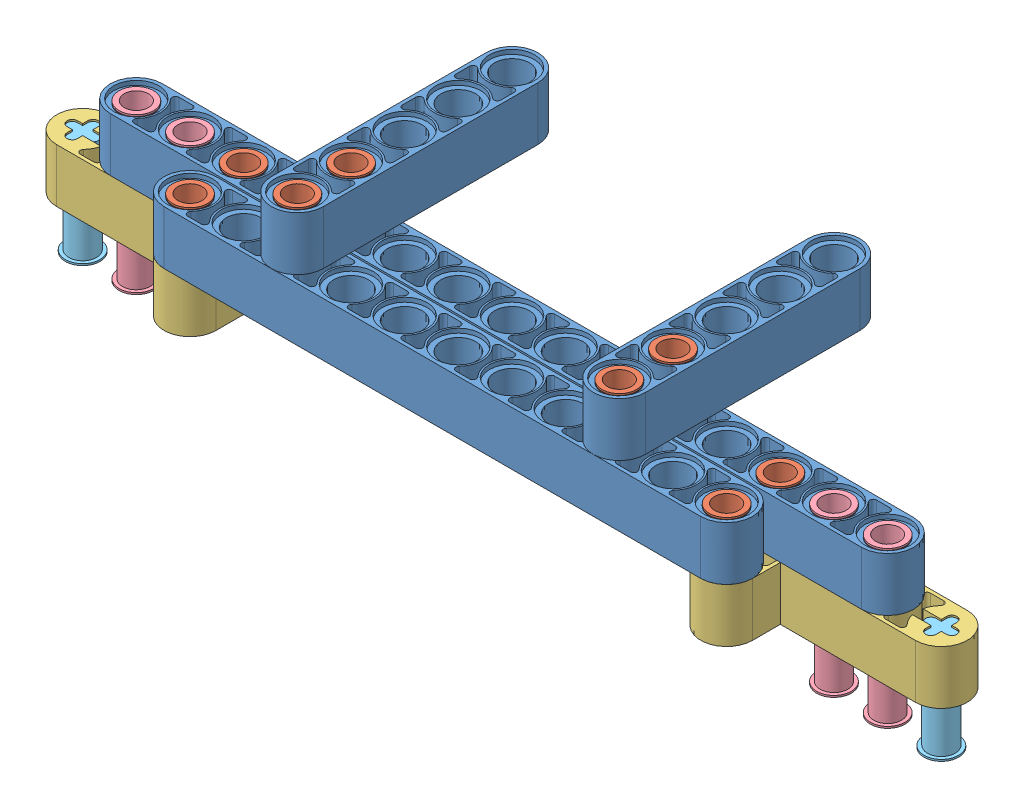
SolidWorks assembly horizontal_connector, configuration Default. Lengths in mm.
Overall size (133.6 31.24 39.12).
20 component instances, 5 part files, 60 mates.
Components (placement in the parent):
- All_Straight-1: All_Straight [Eleven] at (31.496 0 0) x (1 0 0) z (0 1 0) size (86.36 7.62 7.87)
- BlackConnectorSmall-1: BlackConnectorSmall [Default] at (39.37 7.62 0) x (0 -1 0) z (0 0 1) size (15.24 5.59 5.59)
- BlackConnectorSmall-2: BlackConnectorSmall [Default] at (-39.37 7.62 0) x (0 -1 0) z (0 0 1) size (15.24 5.59 5.59)
- BlackConnectorSmall-4: BlackConnectorSmall [Default] at (-23.622 0.254 0) x (0 1 0) z (0 0 -1) size (15.24 5.59 5.59)
- BlackConnectorSmall-5: BlackConnectorSmall [Default] at (23.622 0.254 0) x (0 1 0) z (0 0 -1) size (15.24 5.59 5.59)
- L_Two_Four_90degrees-1: L_Two_Four_90degrees [Default] at (47.4776 -6.6697 -16.0899) x (1 0 0) z (0 -1 0) size (31.24 15.49 7.87)
- L_Two_Four_90degrees-3: L_Two_Four_90degrees [Default] at (-47.4776 -1.2043 -16.0899) x (-1 0 0) z (0 1 0) size (31.24 15.49 7.87)
- BlackConnectorSmall-6: BlackConnectorSmall [Default] at (-39.37 -7.62 -7.874) x (0 1 0) z (0 0 -1) size (15.24 5.59 5.59)
- BlackConnectorSmall-7: BlackConnectorSmall [Default] at (39.37 -7.62 -7.874) x (0 1 0) z (0 0 -1) size (15.24 5.59 5.59)
- BlueConnectorLong-1: BlueConnectorLong [Default] at (47.244 7.62 -7.874) x (0 -1 0) z (-1 0 0) size (22.86 5.59 5.59)
- BlueConnectorLong-2: BlueConnectorLong [Default] at (55.118 7.62 -7.874) x (0 -1 0) z (-1 0 0) size (22.86 5.59 5.59)
- BlueConnectorLong-3: BlueConnectorLong [Default] at (-47.244 7.62 -7.874) x (0 -1 0) z (0 0 1) size (22.86 5.59 5.59)
- BlueConnectorLong-4: BlueConnectorLong [Default] at (-55.118 7.62 -7.874) x (0 -1 0) z (0 0 1) size (22.86 5.59 5.59)
- All_Straight-3: All_Straight [Fifteen] at (47.244 0 -7.874) x (1 0 0) z (0 1 0) size (117.86 7.62 7.87)
- BlackConnectorSmall-8: BlackConnectorSmall [Default] at (23.622 0.254 -7.874) x (0 1 0) z (0 0 -1) size (15.24 5.59 5.59)
- BlackConnectorSmall-9: BlackConnectorSmall [Default] at (-23.622 0.254 -7.874) x (0 1 0) z (0 0 -1) size (15.24 5.59 5.59)
- All_Straight-4: All_Straight [Five] at (-23.622 15.748 -7.874) x (0 0 1) z (0 -1 0) size (39.12 7.62 7.87)
- All_Straight-5: All_Straight [Five] at (23.622 15.748 -7.874) x (0 0 1) z (0 -1 0) size (39.12 7.62 7.87)
- BlueConnectorCross_Tube-1: BlueConnectorCross_Tube [Default] at (62.992 -7.874 -7.874) x (0 -1 0) z (0 0 1) size (15.24 5.08 5.08)
- BlueConnectorCross_Tube-2: BlueConnectorCross_Tube [Default] at (-62.992 -7.874 -7.874) x (0 -1 0) z (0 0 -1) size (15.24 5.08 5.08)
Mates (geometry in assembly coordinates):
- Coincident1: coincident aligned: plane of All_Straight-1 through (31.496 0 0) normal (0 1 0); plane of assembly through (0 0 0) normal (0 1 0)
- Coincident2: coincident anti-aligned: plane of All_Straight-1 through (31.496 0 0) normal (0 0 -1); plane of assembly through (0 0 0) normal (0 0 1)
- Concentric1: concentric: cylinder of All_Straight-1 through (0 3.937 0) axis (0 -1 0) radius 2.54; point of assembly
- Concentric2: concentric anti-aligned: cylinder of All_Straight-1 through (39.37 3.937 0) axis (0 -1 0) radius 2.54; cylinder of BlackConnectorSmall-1 through (39.37 7.62 0) axis (0 1 0) radius 2.032
- Parallel2: parallel aligned: plane of BlackConnectorSmall-1; plane of assembly through (0 0 0) normal (1 0 0)
- Concentric3: concentric anti-aligned: cylinder of All_Straight-1 through (-39.37 3.937 0) axis (0 -1 0) radius 2.54; cylinder of BlackConnectorSmall-2 through (-39.37 7.62 0) axis (0 1 0) radius 2.032
- Parallel3: parallel aligned: plane of BlackConnectorSmall-2; plane of assembly through (0 0 0) normal (1 0 0)
- Concentric5: concentric aligned: cylinder of All_Straight-1 through (-23.622 3.937 0) axis (0 -1 0) radius 2.54; cylinder of BlackConnectorSmall-4 through (-23.622 0.254 0) axis (0 -1 0) radius 2.032
- Parallel4: parallel aligned: plane of BlackConnectorSmall-4; plane of assembly through (0 0 0) normal (1 0 0)
- Concentric6: concentric aligned: cylinder of All_Straight-1 through (23.622 3.937 0) axis (0 -1 0) radius 2.54; cylinder of BlackConnectorSmall-5 through (23.622 0.254 0) axis (0 -1 0) radius 2.032
- Parallel5: parallel aligned: plane of BlackConnectorSmall-5; plane of assembly through (0 0 0) normal (1 0 0)
- Concentric7: concentric aligned: cylinder of BlackConnectorSmall-1 through (39.37 7.62 0) axis (0 1 0) radius 2.032; cylinder of L_Two_Four_90degrees-1 through (39.37 -3.937 0) axis (0 1 0) radius 2.54
- Parallel6: parallel aligned: plane of All_Straight-1 through (31.496 3.937 3.81) normal (0 0 1); plane of L_Two_Four_90degrees-1 through (55.118 -4.064 -4.064) normal (0 0 1)
- Concentric9: concentric anti-aligned: cylinder of BlackConnectorSmall-2 through (-39.37 7.62 0) axis (0 1 0) radius 2.032; cylinder of L_Two_Four_90degrees-3 through (-39.37 -3.937 0) axis (0 -1 0) radius 2.54
- Parallel11: parallel aligned: plane of All_Straight-1 through (31.496 3.937 -3.81) normal (0 0 -1); plane of L_Two_Four_90degrees-3 through (-55.118 -3.81 -11.684) normal (0 0 -1)
- Concentric10: concentric aligned: cylinder of L_Two_Four_90degrees-3 through (-39.37 -3.937 -7.874) axis (0 -1 0) radius 2.54; cylinder of BlackConnectorSmall-6 through (-39.37 -7.62 -7.874) axis (0 -1 0) radius 2.032
- Parallel12: parallel aligned: plane of BlackConnectorSmall-6; plane of assembly through (0 0 0) normal (1 0 0)
- Concentric11: concentric anti-aligned: cylinder of L_Two_Four_90degrees-1 through (39.37 -3.937 -7.874) axis (0 1 0) radius 2.54; cylinder of BlackConnectorSmall-7 through (39.37 -7.62 -7.874) axis (0 -1 0) radius 2.032
- Parallel13: parallel aligned: plane of BlackConnectorSmall-7; plane of assembly through (0 0 0) normal (1 0 0)
- Concentric12: concentric aligned: cylinder of L_Two_Four_90degrees-1 through (47.244 -4.064 -7.874) axis (0 1 0) radius 2.54; cylinder of BlueConnectorLong-1 through (47.244 7.62 -7.874) axis (0 1 0) radius 2.032
- Coincident21: coincident anti-aligned: plane of L_Two_Four_90degrees-1 through (47.244 -0.635 -7.874) normal (0 1 0); plane of BlueConnectorLong-1 through (47.244 -0.635 -5.842) normal (0 -1 0)
- Parallel14: parallel anti-aligned: plane of BlueConnectorLong-1 through (47.244 7.62 -7.874) normal (-1 0 0); plane of assembly through (0 0 0) normal (1 0 0)
- Concentric19: concentric aligned: cylinder of L_Two_Four_90degrees-1 through (55.118 -4.064 -7.874) axis (0 1 0) radius 2.54; cylinder of BlueConnectorLong-2 through (55.118 7.62 -7.874) axis (0 1 0) radius 2.032
- Coincident26: coincident anti-aligned: plane of L_Two_Four_90degrees-1 through (55.118 -0.635 -7.874) normal (0 1 0); plane of BlueConnectorLong-2 through (55.118 -0.635 -5.842) normal (0 -1 0)
- Parallel17: parallel anti-aligned: plane of BlueConnectorLong-2 through (55.118 7.62 -7.874) normal (-1 0 0); plane of assembly through (0 0 0) normal (1 0 0)
- Concentric20: concentric anti-aligned: cylinder of L_Two_Four_90degrees-3 through (-47.244 -3.81 -7.874) axis (0 -1 0) radius 2.54; cylinder of BlueConnectorLong-3 through (-47.244 7.62 -7.874) axis (0 1 0) radius 2.032
- Coincident27: coincident anti-aligned: plane of L_Two_Four_90degrees-3 through (-47.244 -0.635 -7.874) normal (0 1 0); plane of BlueConnectorLong-3 through (-45.212 -0.635 -7.874) normal (0 -1 0)
- Parallel18: parallel aligned: plane of BlueConnectorLong-3; plane of assembly through (0 0 0) normal (1 0 0)
- Concentric21: concentric anti-aligned: cylinder of L_Two_Four_90degrees-3 through (-55.118 -3.81 -7.874) axis (0 -1 0) radius 2.54; cylinder of BlueConnectorLong-4 through (-55.118 7.62 -7.874) axis (0 1 0) radius 2.032
- Coincident29: coincident anti-aligned: plane of L_Two_Four_90degrees-3 through (-55.118 -0.635 -7.874) normal (0 1 0); plane of BlueConnectorLong-4 through (-53.086 -0.635 -7.874) normal (0 -1 0)
- Parallel19: parallel aligned: plane of BlueConnectorLong-4; plane of assembly through (0 0 0) normal (1 0 0)
- Concentric23: concentric aligned: cylinder of All_Straight-3 through (23.622 3.937 -7.874) axis (0 -1 0) radius 2.54; cylinder of BlackConnectorSmall-8 through (23.622 0.254 -7.874) axis (0 -1 0) radius 2.032
- Parallel21: parallel aligned: plane of BlackConnectorSmall-8; plane of assembly through (0 0 0) normal (1 0 0)
- Concentric24: concentric aligned: cylinder of All_Straight-3 through (-23.622 3.937 -7.874) axis (0 -1 0) radius 2.54; cylinder of BlackConnectorSmall-9 through (-23.622 0.254 -7.874) axis (0 -1 0) radius 2.032
- Parallel22: parallel aligned: plane of BlackConnectorSmall-9; plane of assembly through (0 0 0) normal (1 0 0)
- Concentric25: concentric anti-aligned: cylinder of BlackConnectorSmall-4 through (-23.622 0.254 0) axis (0 -1 0) radius 2.032; cylinder of All_Straight-4 through (-23.622 11.811 0) axis (0 1 0) radius 2.54
- Concentric26: concentric anti-aligned: cylinder of BlackConnectorSmall-9 through (-23.622 0.254 -7.874) axis (0 -1 0) radius 2.032; cylinder of All_Straight-4 through (-23.622 11.811 -7.874) axis (0 1 0) radius 2.54
- Coincident34: coincident aligned: circle of BlackConnectorSmall-4; plane of All_Straight-4 through (-23.622 8.509 0) normal (0 -1 0)
- Concentric27: concentric anti-aligned: cylinder of BlackConnectorSmall-5 through (23.622 0.254 0) axis (0 -1 0) radius 2.032; cylinder of All_Straight-5 through (23.622 11.811 0) axis (0 1 0) radius 2.54
- Concentric28: concentric anti-aligned: cylinder of BlackConnectorSmall-8 through (23.622 0.254 -7.874) axis (0 -1 0) radius 2.032; cylinder of All_Straight-5 through (23.622 11.811 -7.874) axis (0 1 0) radius 2.54
- Coincident35: coincident anti-aligned: plane of BlackConnectorSmall-5 through (25.654 8.509 0) normal (0 1 0); plane of All_Straight-5 through (23.622 8.509 0) normal (0 -1 0)
- Concentric29: concentric anti-aligned: cylinder of L_Two_Four_90degrees-1 through (64.516 -4.064 -7.874) axis (0 1 0) radius 0.762; cylinder of BlueConnectorCross_Tube-1 through (64.516 -0.254 -7.874) axis (0 -1 0) radius 0.762
- Coincident36: coincident anti-aligned: plane of L_Two_Four_90degrees-1 through (55.118 -7.874 -30.5586) normal (0 -1 0); plane of BlueConnectorCross_Tube-1 through (64.77 -7.874 -7.874) normal (0 1 0)
- Coincident37: coincident anti-aligned: plane of L_Two_Four_90degrees-1 through (63.754 -4.064 -30.5586) normal (-1 0 0); plane of BlueConnectorCross_Tube-1 through (63.754 -0.254 -8.636) normal (1 0 0)
- Concentric30: concentric aligned: cylinder of L_Two_Four_90degrees-3 through (-64.516 -3.81 -7.874) axis (0 -1 0) radius 0.762; cylinder of BlueConnectorCross_Tube-2 through (-64.516 -0.254 -7.874) axis (0 -1 0) radius 0.762
- Coincident38: coincident anti-aligned: plane of L_Two_Four_90degrees-3 through (-55.118 -7.874 -30.5586) normal (0 -1 0); plane of BlueConnectorCross_Tube-2 through (-64.77 -7.874 -7.874) normal (0 1 0)
- Coincident40: coincident anti-aligned: plane of L_Two_Four_90degrees-3 through (-63.754 -3.81 -30.5586) normal (1 0 0); plane of BlueConnectorCross_Tube-2 through (-63.754 -0.254 -7.112) normal (-1 0 0)
- Coincident41: coincident anti-aligned: plane of All_Straight-1 through (39.37 0.635 0) normal (0 -1 0); plane of BlackConnectorSmall-1 through (42.164 0.635 0) normal (0 1 0)
- Coincident42: coincident anti-aligned: plane of All_Straight-1 through (-39.37 0.635 0) normal (0 -1 0); plane of BlackConnectorSmall-2 through (-36.576 0.635 0) normal (0 1 0)
- Coincident43: coincident anti-aligned: plane of All_Straight-1 through (-23.622 7.239 0) normal (0 1 0); plane of BlackConnectorSmall-4 through (-20.828 7.239 0) normal (0 -1 0)
- Coincident44: coincident anti-aligned: plane of All_Straight-1 through (23.622 7.239 0) normal (0 1 0); plane of BlackConnectorSmall-5 through (26.416 7.239 0) normal (0 -1 0)
- Coincident45: coincident anti-aligned: plane of BlackConnectorSmall-1 through (41.402 -0.635 0) normal (0 -1 0); plane of L_Two_Four_90degrees-1 through (39.37 -0.635 0) normal (0 1 0)
- Coincident47: coincident anti-aligned: plane of BlackConnectorSmall-2 through (-37.338 -0.635 0) normal (0 -1 0); plane of L_Two_Four_90degrees-3 through (-39.37 -0.635 0) normal (0 1 0)
- Coincident48: coincident anti-aligned: plane of L_Two_Four_90degrees-3 through (-39.37 -0.635 -7.874) normal (0 1 0); plane of BlackConnectorSmall-6 through (-36.576 -0.635 -7.874) normal (0 -1 0)
- Coincident49: coincident anti-aligned: plane of L_Two_Four_90degrees-1 through (39.37 -0.635 -7.874) normal (0 1 0); plane of BlackConnectorSmall-7 through (42.164 -0.635 -7.874) normal (0 -1 0)
- Concentric31: concentric anti-aligned: cylinder of BlueConnectorLong-2 through (55.118 7.62 -7.874) axis (0 1 0) radius 2.032; cylinder of All_Straight-3 through (55.118 3.937 -7.874) axis (0 -1 0) radius 2.54
- Concentric32: concentric anti-aligned: cylinder of BlueConnectorLong-4 through (-55.118 7.62 -7.874) axis (0 1 0) radius 2.032; cylinder of All_Straight-3 through (-55.118 3.937 -7.874) axis (0 -1 0) radius 2.54
- Coincident50: coincident anti-aligned: plane of BlueConnectorLong-2 through (55.118 0.635 -5.08) normal (0 1 0); plane of All_Straight-3 through (55.118 0.635 -7.874) normal (0 -1 0)
- Coincident51: coincident anti-aligned: plane of All_Straight-3 through (23.622 7.239 -7.874) normal (0 1 0); plane of BlackConnectorSmall-8 through (26.416 7.239 -7.874) normal (0 -1 0)
- Coincident52: coincident anti-aligned: plane of All_Straight-3 through (-23.622 7.239 -7.874) normal (0 1 0); plane of BlackConnectorSmall-9 through (-20.828 7.239 -7.874) normal (0 -1 0)
